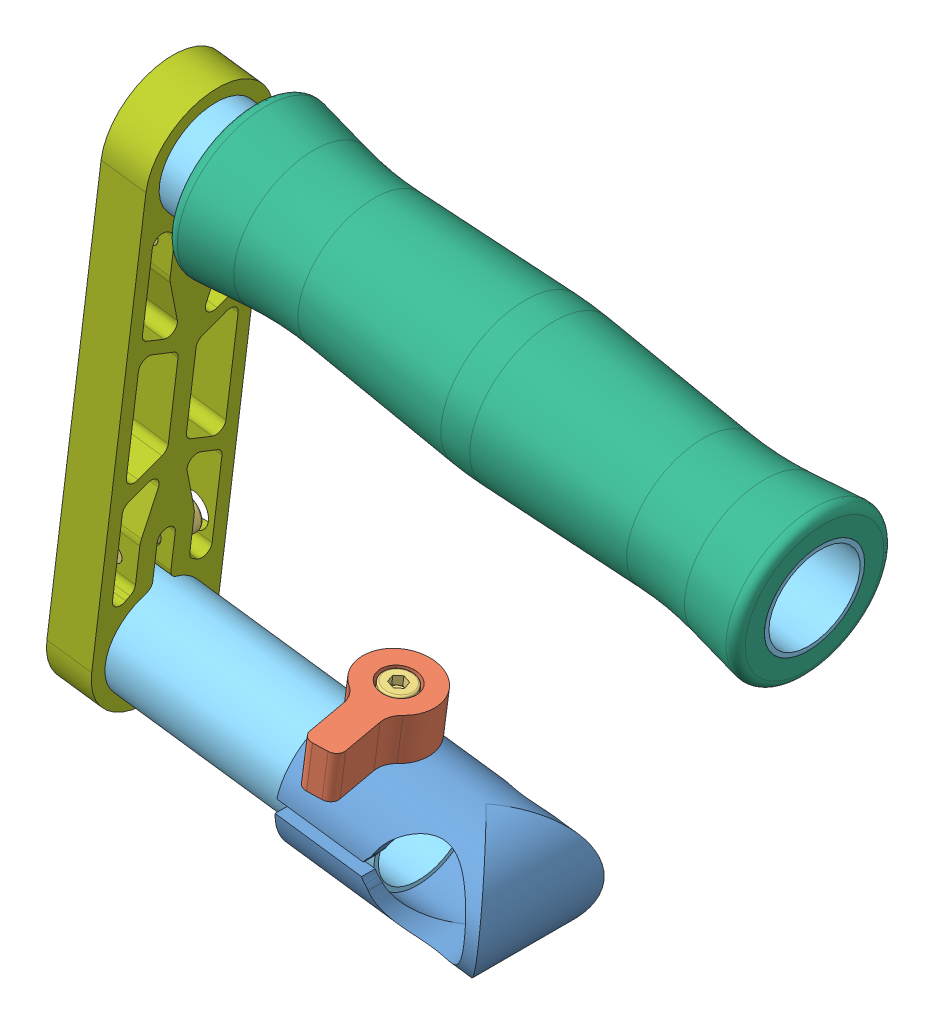
SolidWorks assembly central_handle, configuration По умолчанию. Lengths in mm.
Overall size (161.17 140.73 38.42).
11 component instances, 7 part files, 14 mates.
Components (placement in the parent):
- handle_holder_22mm-3: handle_holder_22mm [По умолчанию] at (-63.3359 116.1259 25.553) x (-0.131896 -0.991264 0) z (-0.991264 0.131896 0) size (28 28 45)
- flag_screw-6: flag_screw [По умолчанию] at (-54.3812 116.8606 -5.7194) x (0.977974 -0.130128 -0.163196) z (0.16177 -0.021525 0.986594) size (16 29 29)
  - flag-1: flag [По умолчанию] at (-48.2962 13.0906 23.7085) size (16 10 29)
  - socket head cap screw_din_1-1: socket head cap screw_din_1 [DIN 912 M4 x 25 --- 25N] at (-48.2962 23.0906 23.7085) x (0 -1 0) z (-0.387543 0 0.921852) size (29 7 7)
  - plain washer 6902 type abc_din-1: plain washer 6902 type abc_din [DIN 6902-A4.55] at (-48.2962 13.0906 23.7085) x (0 -1 0) z (-0.000413 0 1) size (1 10 10)
- pipe_22_2_500-4: pipe_22_2_500 [70mm] at (-89.1087 119.5552 25.553) x (0.055289 0.415526 0.907899) z (-0.991264 0.131896 0) size (22 22 70)
- pipe_22_2_500-5: pipe_22_2_500 [150mm] at (-145.3085 227.9071 26.7514) x (0.017358 0.130458 -0.991302) z (0.991264 -0.131896 0) size (22 22 145)
- neopren-3: neopren [По умолчанию] at (-1.5753 208.7822 26.7514) x (-0.003243 -0.024374 -0.999698) z (-0.131856 -0.990964 0.024588) size (34.36 127 34.36)
- adapter_22_22_mod1-1: adapter_22_22_mod1 [По умолчанию] at (-141.9902 177.0286 26.1522) x (-0.001581 -0.011879 0.999928) z (-0.991264 0.131896 0) size (28 128 10)
- socket head cap screw_din_1-12: socket head cap screw_din_1 [DIN 912 M4 x 12 --- 12N] at (-142.5596 210.6585 16.5501) x (-0.001581 -0.011879 0.999928) z (-0.999904 -0.013767 -0.001744) size (16 7 7)
- socket head cap screw_din_1-13: socket head cap screw_din_1 [DIN 912 M4 x 12 --- 12N] at (-151.3019 144.9552 15.7557) x (-0.001581 -0.011879 0.999928) z (-0.999904 -0.013767 -0.001744) size (16 7 7)
Mates (geometry in assembly coordinates):
- Концентричный32: concentric aligned: cylinder of handle_holder_22mm-3 through (-96.1836 134.6199 25.553) axis (0.131896 0.991264 0) radius 2.25; cylinder of flag_screw-6/socket head cap screw_din_1-1 through (-90.545 176.9965 25.553) axis (0.131896 0.991264 0) radius 2
- Касательность5: tangent anti-aligned: cylinder of handle_holder_22mm-3 through (-107.9427 122.0612 25.553) axis (0.991264 -0.131896 0) radius 14; plane of flag_screw-6/plain washer 6902 type abc_din-1 through (-96.1836 134.6199 25.553) normal (-0.131896 -0.991264 0)
- Концентричный37: concentric anti-aligned: cylinder of handle_holder_22mm-3 through (-77.2136 117.9724 25.553) axis (-0.991264 0.131896 0) radius 11; cylinder of pipe_22_2_500-4 through (-158.4972 128.7879 25.553) axis (0.991264 -0.131896 0) radius 11
- Расстояние4: distance = 51 mm aligned: plane of pipe_22_2_500-4 through (-158.4972 128.7879 25.553) normal (-0.991264 0.131896 0); plane of handle_holder_22mm-3 through (-107.9427 122.0612 25.553) normal (-0.991264 0.131896 0)
- Концентричный38: concentric anti-aligned: cylinder of pipe_22_2_500-5 through (-1.5753 208.7822 26.7514) axis (-0.991264 0.131896 0) radius 11; cylinder of neopren-3 through (-127.4658 225.533 26.7514) axis (0.991264 -0.131896 0) radius 11
- Совпадение50: coincident aligned: plane of pipe_22_2_500-5 through (-1.5753 208.7822 26.7514) normal (0.991264 -0.131896 0); plane of neopren-3 through (-1.5753 208.7822 26.7514) normal (0.991264 -0.131896 0)
- Концентричный39: concentric anti-aligned: cylinder of pipe_22_2_500-4 through (-158.4972 128.7879 25.553) axis (0.991264 -0.131896 0) radius 11; cylinder of adapter_22_22_mod1-1 through (-148.5846 127.4689 25.553) axis (-0.991264 0.131896 0) radius 11
- Совпадение51: coincident aligned: plane of pipe_22_2_500-4 through (-158.4972 128.7879 25.553) normal (-0.991264 0.131896 0); plane of adapter_22_22_mod1-1 through (-158.4972 128.7879 25.553) normal (-0.991264 0.131896 0)
- Концентричный40: concentric aligned: cylinder of pipe_22_2_500-5 through (-1.5753 208.7822 26.7514) axis (-0.991264 0.131896 0) radius 11; cylinder of adapter_22_22_mod1-1 through (-135.3959 226.5882 26.7514) axis (-0.991264 0.131896 0) radius 11
- Концентричный41: concentric aligned: cylinder of adapter_22_22_mod1-1 through (-142.5659 210.611 20.5498) axis (0.001581 0.011879 -0.999928) radius 2.25; cylinder of socket head cap screw_din_1-12 through (-142.5094 211.0357 -15.1976) axis (0.001581 0.011879 -0.999928) radius 3.5
- Совпадение52: coincident anti-aligned: plane of adapter_22_22_mod1-1 through (-138.3726 204.2171 20.4805) normal (0.001581 0.011879 -0.999928); plane of socket head cap screw_din_1-12 through (-142.6141 214.1104 20.5913) normal (-0.001581 -0.011879 0.999928)
- Концентричный42: concentric aligned: cylinder of adapter_22_22_mod1-1 through (-151.3083 144.9076 19.7554) axis (0.001581 0.011879 -0.999928) radius 2.25; cylinder of socket head cap screw_din_1-13 through (-151.2517 145.3323 -15.992) axis (0.001581 0.011879 -0.999928) radius 3.5
- Совпадение53: coincident anti-aligned: plane of adapter_22_22_mod1-1 through (-145.5889 149.9826 19.8248) normal (0.001581 0.011879 -0.999928); plane of socket head cap screw_din_1-13 through (-151.3565 148.4071 19.7969) normal (-0.001581 -0.011879 0.999928)
- Совпадение54: coincident aligned: plane of pipe_22_2_500-5 through (-145.3085 227.9071 26.7514) normal (-0.991264 0.131896 0); plane of adapter_22_22_mod1-1 through (-158.4972 128.7879 25.553) normal (-0.991264 0.131896 0)
